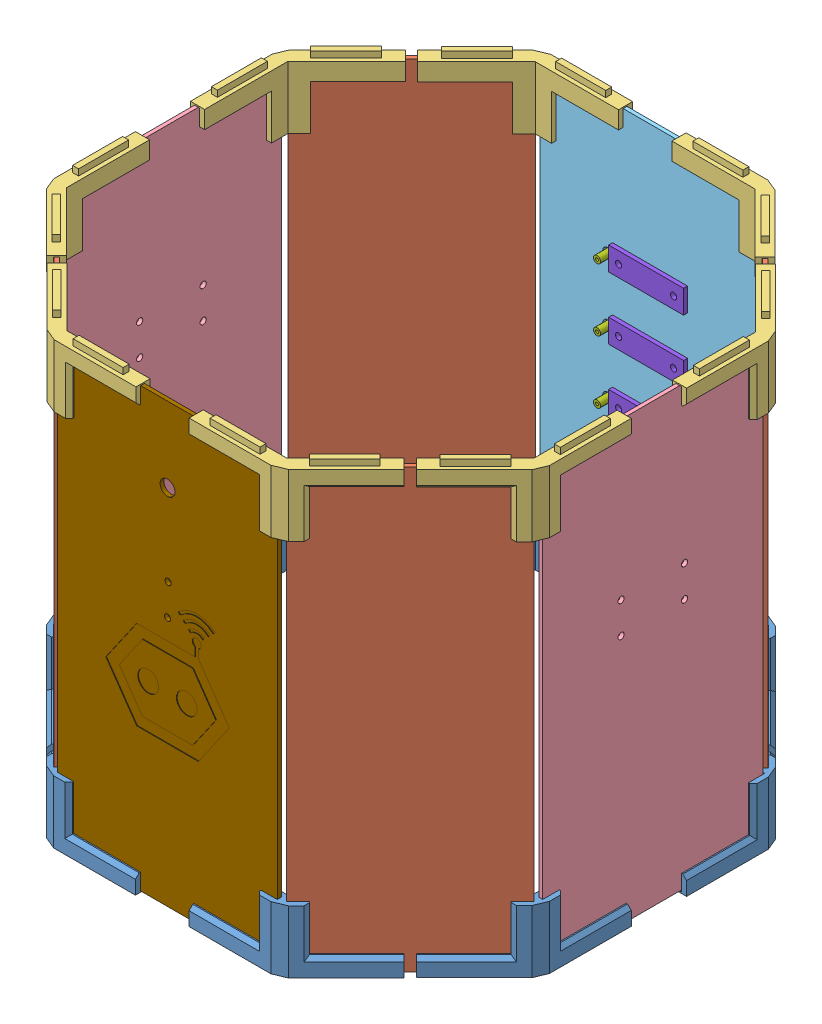
SolidWorks assembly Assem_Body_turtle, configuration Default. Lengths in mm.
Overall size (469.21 357 467.86).
41 component instances, 9 part files, 74 mates.
Components (placement in the parent):
- Links_ButtomOfBody-1: Links_ButtomOfBody [Default] at (-117.5632 60.4705 15.387) size (58.32 50 121.51)
- Body_Angled_Panel_Turtle-1: Body_Angled_Panel_Turtle [Default] at (-124.2129 61.4705 12.4372) x (0.707106 0 -0.707108) z (0 -1 0) size (140 3 350)
- Links_ButtomOfBody-2: Links_ButtomOfBody [Default] at (-17.44 60.4705 -81.6082) x (0.707108 0 0.707106) z (-0.707106 0 0.707108) size (58.32 50 121.51)
- Links_ButtomOfBody-3: Links_ButtomOfBody [Default] at (-120.488 60.4705 190.7707) x (0.707108 0 -0.707106) z (0.707106 0 0.707108) size (58.32 50 121.51)
- Links_ButtomOfBody-4: Links_ButtomOfBody [Default] at (158.1559 60.4705 -79.6088) x (0.000004 0 1) z (-1 0 0.000004) size (58.32 50 121.51)
- Body_Angled_Panel_Turtle-2: Body_Angled_Panel_Turtle [Default] at (161.1056 61.4705 -86.2586) x (0.707111 0 0.707103) z (0 -1 0) size (140 3 350)
- Body_Angled_Panel_Turtle-3: Body_Angled_Panel_Turtle [Default] at (-125.2256 411.4705 198.3367) x (0.707106 0 0.707108) z (0 1 0) size (140 3 350)
- Links_ButtomOfBody-5: Links_ButtomOfBody [Default] at (255.3635 60.4705 20.3019) x (-0.707103 0 0.707111) z (-0.707111 0 -0.707103) size (58.32 50 121.51)
- Links_ButtomOfBody-6: Links_ButtomOfBody [Default] at (-23.2811 60.4705 290.6821) x (0.000004 0 -1) z (1 0 0.000004) size (58.32 50 121.51)
- Links_ButtomOfBody-7: Links_ButtomOfBody [Default] at (152.3148 60.4705 292.8948) x (-0.707103 0 -0.707111) z (0.707111 0 -0.707103) size (58.32 50 121.51)
- Body_Angled_Panel_Turtle-4: Body_Angled_Panel_Turtle [Default] at (159.8808 411.4705 297.6325) x (0.707111 0 -0.707103) z (0 1 0) size (140 3 350)
- Links_ButtomOfBody-8: Links_ButtomOfBody [Default] at (252.0144 60.4705 195.4761) x (-1 0 -0.000007) z (0.000007 0 -1) size (58.32 50 121.51)
- Links_TopOfBody-1: Links_TopOfBody [Default] at (156.7189 412.4705 290.7706) x (0.000004 0 -1) z (-1 0 -0.000004) size (58.32 55 121.51)
- Links_TopOfBody-2: Links_TopOfBody [Default] at (254.1387 412.4705 191.072) x (-0.707103 0 -0.707111) z (-0.707111 0 0.707103) size (58.32 55 121.51)
- Links_TopOfBody-3: Links_TopOfBody [Default] at (-18.4526 412.4705 292.3821) x (0.707108 0 -0.707106) z (-0.707106 0 -0.707108) size (58.32 55 121.51)
- Links_TopOfBody-4: Links_TopOfBody [Default] at (-118.5758 412.4705 195.387) x (1 0 0) z (0 0 -1) size (58.32 55 121.51)
- Links_TopOfBody-5: Links_TopOfBody [Default] at (-22.0563 412.4705 -79.696) x (0.000004 0 1) z (1 0 -0.000004) size (58.32 55 121.51)
- Links_TopOfBody-6: Links_TopOfBody [Default] at (-119.4753 412.4705 20.0033) x (0.707108 0 0.707106) z (0.707106 0 -0.707108) size (58.32 55 121.51)
- Links_TopOfBody-7: Links_TopOfBody [Default] at (153.3274 412.4705 -81.3088) x (-0.707103 0 0.707111) z (0.707111 0 0.707103) size (58.32 55 121.51)
- Links_TopOfBody-8: Links_TopOfBody [Default] at (253.4513 412.4705 15.6857) x (-1 0 0.000007) z (0.000007 0 1) size (58.32 55 121.51)
- Body_Side_Panel_Turtle-3: Body_Side_Panel_Turtle [Default] at (-124.2758 61.4705 17.387) x (0 0 1) z (0 -1 0) size (176 3 350)
- Front_Panel_aluminiumContact_Turtle-1: Front_Panel_aluminiumContact_Turtle [Default] at (-275.2247 514.6339 -363.4416) x (1 0 -0.000004) z (0 -0.999584 -0.02885) size (176 20.62 349.94)
  - Body_Front_Panel_aluContact_Turtle-1: Body_Front_Panel_aluContact_Turtle [Default] at (255.1674 288.3056 445.031) x (1 0 0) z (0 0.02885 0.999584) size (176 3 350)
  - ContactAluFer-1: ContactAluFer [Default] at (317.0703 243.8583 286.4012) x (1 0 0) z (0 0.02885 0.999584) size (80 15.57 25.3)
    - Contact_barreAlu-1: Contact_barreAlu [Default] at (-13.9029 35.8024 53.6961) size (80 3.2 25.3)
    - ConnecteurAAnneau-1: ConnecteurAAnneau [Default] at (4.0971 39.0024 66.3461) x (0 0 1) z (-1 0 0) size (11.92 12.37 20.64)
    - Contact_barreFer-1: Contact_barreFer [Default] at (-3.9029 42.8524 75.6811) size (60 3.15 18.67)
  - ContactAluFer-2: ContactAluFer [Default] at (317.0703 240.9733 186.4428) x (1 0 0) z (0 0.02885 0.999584) size (80 15.57 25.3)
    - Contact_barreAlu-1: Contact_barreAlu [Default] at (-13.9029 35.8024 53.6961) size (80 3.2 25.3)
    - ConnecteurAAnneau-1: ConnecteurAAnneau [Default] at (4.0971 39.0024 66.3461) x (0 0 1) z (-1 0 0) size (11.92 12.37 20.64)
    - Contact_barreFer-1: Contact_barreFer [Default] at (-3.9029 42.8524 75.6811) size (60 3.15 18.67)
  - ContactAluFer-3: ContactAluFer [Default] at (317.0703 239.5308 136.4636) x (1 0 0) z (0 0.02885 0.999584) size (80 15.57 25.3)
    - Contact_barreAlu-1: Contact_barreAlu [Default] at (-13.9029 35.8024 53.6961) size (80 3.2 25.3)
    - ConnecteurAAnneau-1: ConnecteurAAnneau [Default] at (4.0971 39.0024 66.3461) x (0 0 1) z (-1 0 0) size (11.92 12.37 20.64)
    - Contact_barreFer-1: Contact_barreFer [Default] at (-3.9029 42.8524 75.6811) size (60 3.15 18.67)
  - ContactAluFer-4: ContactAluFer [Default] at (317.0703 242.4158 236.422) x (1 0 0) z (0 0.02885 0.999584) size (80 15.57 25.3)
    - Contact_barreAlu-1: Contact_barreAlu [Default] at (-13.9029 35.8024 53.6961) size (80 3.2 25.3)
    - ConnecteurAAnneau-1: ConnecteurAAnneau [Default] at (4.0971 39.0024 66.3461) x (0 0 1) z (-1 0 0) size (11.92 12.37 20.64)
    - Contact_barreFer-1: Contact_barreFer [Default] at (-3.9029 42.8524 75.6811) size (60 3.15 18.67)
- Body_Side_Panel_Turtle-4: Body_Side_Panel_Turtle [Default] at (257.9265 61.4705 193.6883) x (0.000007 0 -1) z (0 -1 0) size (176 3 350)
- Body_Back_Panel_Turtle-1: Body_Back_Panel_Turtle [Default] at (154.931 61.4705 299.6827) x (-1 0 -0.000004) z (0 -1 0) size (176 3 350)
Mates (geometry in assembly coordinates):
- Coincident59: coincident anti-aligned: plane of CoinButtom_Bas-1 through (-112.8992 110.4705 5.3661) normal (-0.707108 0 -0.707106); plane of Side_angle-1 through (-122.0916 61.4705 14.5585) normal (0.707108 0 0.707106)
- Coincident60: coincident anti-aligned: plane of CoinButtom_Bas-1 through (-112.8992 61.4705 5.3661) normal (0 1 0); plane of Side_angle-1 through (-122.0916 61.4705 14.5585) normal (0 -1 0)
- Coincident61: coincident anti-aligned: plane of CoinButtom_Bas-1 through (-122.0916 110.4705 14.5585) normal (0.707106 0 -0.707108); plane of Side_angle-1 through (-122.0916 61.4705 14.5585) normal (-0.707106 0 0.707108)
- Coincident62: coincident anti-aligned: plane of CoinButtom_Bas-2 through (-25.2181 110.4705 -86.5579) normal (0.707108 0 0.707106); plane of Side_angle-1 through (-124.2129 61.4705 12.4372) normal (-0.707108 0 -0.707106)
- Coincident63: coincident anti-aligned: plane of Side_angle-1 through (-23.0968 61.4705 -84.4366) normal (0.707106 0 -0.707108); plane of CoinButtom_Bas-2 through (-22.8847 110.4705 -84.2245) normal (-0.707106 0 0.707108)
- Coincident64: coincident anti-aligned: plane of Side_angle-1 through (-122.0916 61.4705 14.5585) normal (0 -1 0); plane of CoinButtom_Bas-2 through (-32.0771 61.4705 -75.032) normal (0 1 0)
- Coincident75: coincident anti-aligned: plane of CoinButtom_Bas-4 through (168.1767 110.4705 -74.9449) normal (0.707103 0 -0.707111); plane of Side_angle-2 through (158.9843 61.4705 -84.1372) normal (-0.707103 0 0.707111)
- Coincident76: coincident anti-aligned: plane of CoinButtom_Bas-4 through (168.1767 61.4705 -74.9449) normal (0 1 0); plane of Side_angle-2 through (158.9843 61.4705 -84.1372) normal (0 -1 0)
- Coincident77: coincident anti-aligned: plane of CoinButtom_Bas-4 through (158.9843 110.4705 -84.1372) normal (0.707111 0 0.707103); plane of Side_angle-2 through (158.9843 61.4705 -84.1372) normal (-0.707111 0 -0.707103)
- Coincident79: coincident anti-aligned: plane of Links_ButtomOfBody-3 through (-113.9119 110.4705 205.4078) normal (-0.707108 0 0.707106); plane of Side_angle-3 through (-123.1043 411.4705 196.2154) normal (0.707108 0 -0.707106)
- Coincident80: coincident anti-aligned: plane of Links_ButtomOfBody-3 through (-123.1043 110.4705 196.2154) normal (0.707106 0 0.707108); plane of Side_angle-3 through (-123.1043 411.4705 196.2154) normal (-0.707106 0 -0.707108)
- Coincident81: coincident anti-aligned: plane of Links_ButtomOfBody-3 through (-113.9119 61.4705 205.4078) normal (0 1 0); plane of Side_angle-3 through (-123.1043 61.4705 196.2154) normal (0 -1 0)
- Coincident85: coincident anti-aligned: plane of Side_angle-3 through (-123.1043 411.4705 196.2154) normal (0.707108 0 -0.707106); plane of Links_ButtomOfBody-6 through (-33.3019 110.4705 286.0181) normal (-0.707108 0 0.707106)
- Coincident86: coincident anti-aligned: plane of Side_angle-3 through (-123.1043 61.4705 196.2154) normal (0 -1 0); plane of Links_ButtomOfBody-6 through (-33.3019 61.4705 286.0181) normal (0 1 0)
- Coincident87: coincident anti-aligned: plane of Side_angle-3 through (-24.1095 411.4705 295.2105) normal (0.707106 0 0.707108); plane of Links_ButtomOfBody-6 through (-24.1095 110.4705 295.2105) normal (-0.707106 0 -0.707108)
- Coincident94: coincident anti-aligned: plane of Links_ButtomOfBody-7 through (166.9519 110.4705 286.3188) normal (0.707103 0 0.707111); plane of Side_angle-4 through (157.7595 411.4705 295.5111) normal (-0.707103 0 -0.707111)
- Coincident95: coincident anti-aligned: plane of Links_ButtomOfBody-7 through (157.7595 110.4705 295.5111) normal (0.707111 0 -0.707103); plane of Side_angle-4 through (157.7595 411.4705 295.5111) normal (-0.707111 0 0.707103)
- Coincident96: coincident anti-aligned: plane of Links_ButtomOfBody-7 through (166.9519 61.4705 286.3188) normal (0 1 0); plane of Side_angle-4 through (157.7595 61.4705 295.5111) normal (0 -1 0)
- Coincident97: coincident anti-aligned: plane of Side_angle-4 through (159.8808 411.4705 297.6325) normal (0.707103 0 0.707111); plane of Links_ButtomOfBody-8 through (258.8763 110.4705 198.6381) normal (-0.707103 0 -0.707111)
- Coincident99: coincident anti-aligned: plane of Side_angle-4 through (256.7549 411.4705 196.5167) normal (0.707111 0 -0.707103); plane of Links_ButtomOfBody-8 through (256.5428 110.4705 196.3046) normal (-0.707111 0 0.707103)
- Coincident109: coincident anti-aligned: plane of Side_angle-4 through (157.7595 411.4705 295.5111) normal (-0.707103 0 -0.707111); plane of Links_TopOfBody-2 through (247.5625 362.4705 205.7091) normal (0.707103 0 0.707111)
- Coincident110: coincident anti-aligned: plane of Side_angle-4 through (256.7549 411.4705 196.5167) normal (0.707111 0 -0.707103); plane of Links_TopOfBody-2 through (256.7549 362.4705 196.5167) normal (-0.707111 0 0.707103)
- Coincident111: coincident anti-aligned: plane of Side_angle-4 through (157.7595 411.4705 295.5111) normal (0 1 0); plane of Links_TopOfBody-2 through (247.5625 411.4705 205.7091) normal (0 -1 0)
- Coincident116: coincident anti-aligned: plane of Side_angle-3 through (-123.1043 411.4705 196.2154) normal (0.707108 0 -0.707106); plane of Links_TopOfBody-4 through (-113.9119 362.4705 205.4078) normal (-0.707108 0 0.707106)
- Coincident117: coincident anti-aligned: plane of Side_angle-3 through (-123.1043 411.4705 196.2154) normal (-0.707106 0 -0.707108); plane of Links_TopOfBody-4 through (-123.1043 362.4705 196.2154) normal (0.707106 0 0.707108)
- Coincident118: coincident anti-aligned: plane of Side_angle-3 through (-123.1043 411.4705 196.2154) normal (0 1 0); plane of Links_TopOfBody-4 through (-113.9119 411.4705 205.4078) normal (0 -1 0)
- Coincident128: coincident anti-aligned: plane of Side_angle-2 through (158.9843 61.4705 -84.1372) normal (-0.707103 0 0.707111); plane of Links_TopOfBody-8 through (248.7873 362.4705 5.6649) normal (0.707103 0 -0.707111)
- Coincident129: coincident anti-aligned: plane of Side_angle-2 through (257.9798 61.4705 14.8572) normal (0.707111 0 0.707103); plane of Links_TopOfBody-8 through (257.9798 362.4705 14.8572) normal (-0.707111 0 -0.707103)
- Coincident130: coincident anti-aligned: plane of Side_angle-2 through (158.9843 411.4705 -84.1372) normal (0 1 0); plane of Links_TopOfBody-8 through (248.7873 411.4705 5.6649) normal (0 -1 0)
- Coincident134: coincident anti-aligned: plane of Side_angle-3 through (-125.2256 411.4705 198.3367) normal (-0.707108 0 0.707106); plane of Links_TopOfBody-3 through (-26.2308 362.4705 297.3318) normal (0.707108 0 -0.707106)
- Coincident135: coincident anti-aligned: plane of Side_angle-3 through (-123.1043 411.4705 196.2154) normal (0 1 0); plane of Links_TopOfBody-3 through (-33.0897 411.4705 285.806) normal (0 -1 0)
- Coincident136: coincident aligned: line of Side_angle-3 through (-24.1095 411.4705 295.2105) axis (-0.707108 0 0.707106); line of Links_TopOfBody-3 through (-23.8974 411.4705 294.9984) axis (-0.707108 0 0.707106)
- Coincident140: coincident anti-aligned: plane of Side_angle-1 through (-122.0916 61.4705 14.5585) normal (-0.707106 0 0.707108); plane of Links_TopOfBody-6 through (-122.0916 362.4705 14.5585) normal (0.707106 0 -0.707108)
- Coincident141: coincident anti-aligned: plane of Side_angle-1 through (-122.0916 61.4705 14.5585) normal (0.707108 0 0.707106); plane of Links_TopOfBody-6 through (-112.8992 362.4705 5.3661) normal (-0.707108 0 -0.707106)
- Coincident142: coincident aligned: line of Side_angle-1 through (-122.0916 411.4705 14.5585) axis (-0.707108 0 -0.707106); line of Links_TopOfBody-6 through (-122.0916 411.4705 14.5585) axis (-0.707108 0 -0.707106)
- Coincident149: coincident anti-aligned: plane of Links_ButtomOfBody-5 through (259.1514 110.4705 30.6856) normal (1 0 -0.000007); plane of Side_court_avant_turtle-1 through (259.1513 61.4705 17.6856) normal (-1 0 0.000007)
- Coincident150: coincident anti-aligned: plane of Links_ButtomOfBody-5 through (259.1514 61.4705 30.6856) normal (0 1 0); plane of Side_court_avant_turtle-1 through (259.1513 61.4705 17.6856) normal (0 -1 0)
- Coincident151: coincident aligned: line of Links_TopOfBody-8 through (259.1513 411.4705 17.6856) axis (1 0 -0.000007); line of Side_court_avant_turtle-1 through (259.1513 411.4705 17.6856) axis (1 0 -0.000007)
- Coincident152: coincident anti-aligned: plane of Side_angle-2 through (158.9843 411.4705 -84.1372) normal (0 1 0); plane of Links_TopOfBody-7 through (167.9646 411.4705 -74.7328) normal (0 -1 0)
- Coincident153: coincident anti-aligned: plane of Links_ButtomOfBody-8 through (257.7145 61.4705 180.4762) normal (0 1 0); plane of Side_court_avant_turtle-1 through (259.1513 61.4705 17.6856) normal (0 -1 0)
- Coincident154: coincident anti-aligned: plane of Side_angle-4 through (157.7595 411.4705 295.5111) normal (0 1 0); plane of Links_TopOfBody-1 through (166.7398 411.4705 286.1067) normal (0 -1 0)
- Coincident155: coincident anti-aligned: plane of Side_angle-4 through (157.7595 411.4705 295.5111) normal (-0.707111 0 0.707103); plane of Links_TopOfBody-1 through (157.5473 362.4705 295.299) normal (0.707111 0 -0.707103)
- Coincident156: coincident anti-aligned: plane of Side_angle-4 through (159.8808 411.4705 297.6325) normal (0.707103 0 0.707111); plane of Links_TopOfBody-1 through (159.8808 362.4705 297.6325) normal (-0.707103 0 -0.707111)
- Coincident157: coincident anti-aligned: plane of Links_ButtomOfBody-3 through (-124.2758 110.4705 180.387) normal (-1 0 0); plane of Side_court_turtle-3 through (-124.2758 61.4705 17.387) normal (1 0 0)
- Coincident161: coincident anti-aligned: plane of Links_ButtomOfBody-3 through (-124.2758 61.4705 180.387) normal (0 1 0); plane of Side_court_turtle-3 through (-127.2758 61.4705 17.387) normal (0 -1 0)
- Coincident162: coincident anti-aligned: line of Links_ButtomOfBody-3 through (-124.2758 61.4705 193.387) axis (-1 0 0); line of Side_court_turtle-3 through (-127.2758 61.4705 193.387) axis (1 0 0)
- Coincident163: coincident anti-aligned: plane of Links_TopOfBody-7 through (155.9437 362.4705 -88.3966) normal (0.000004 0 1); plane of Side_court_turtle-1 through (-20.0563 61.4705 -88.396) normal (-0.000004 0 -1)
- Coincident164: coincident anti-aligned: plane of Links_TopOfBody-7 through (142.9437 411.4705 -85.0966) normal (0 -1 0); plane of Side_court_turtle-1 through (-20.0563 411.4705 -85.396) normal (0 1 0)
- Coincident165: coincident aligned: line of Links_TopOfBody-7 through (155.9437 411.4705 -85.0966) axis (-0.000004 0 -1); line of Side_court_turtle-1 through (155.9437 411.4705 -85.3966) axis (-0.000004 0 -1)
- Coincident166: coincident anti-aligned: plane of Links_TopOfBody-1 through (141.7189 362.4705 296.4705) normal (-0.000004 0 1); plane of Side_court_turtle-2 through (-21.2811 61.4705 296.47) normal (0.000004 0 -1)
- Coincident167: coincident anti-aligned: plane of Links_TopOfBody-1 through (141.7189 411.4705 296.4705) normal (0 -1 0); plane of Side_court_turtle-2 through (-21.2811 411.4705 299.47) normal (0 1 0)
- Coincident168: coincident anti-aligned: line of Links_TopOfBody-1 through (154.7189 411.4705 296.4706) axis (-0.000004 0 1); line of Side_court_turtle-2 through (154.7189 411.4705 299.4706) axis (0.000004 0 -1)
- Coincident169: coincident anti-aligned: plane of Links_TopOfBody-3 through (-8.069 411.4705 296.17) normal (0 -1 0); plane of Side_court_turtle-2 through (-21.2811 411.4705 299.47) normal (0 1 0)
- Coincident170: coincident anti-aligned: plane of Links_TopOfBody-3 through (-21.069 362.4705 299.47) normal (0.000004 0 -1); plane of Side_court_turtle-2 through (-21.2811 61.4705 299.47) normal (-0.000004 0 1)
- Coincident171: coincident: line of Links_ButtomOfBody-6 through (-21.2811 61.4705 296.3821) axis (-0.000004 0 1); plane of Side_court_turtle-2 through (-21.2811 61.4705 299.47) normal (-1 0 -0.000004)
- Coincident172: coincident anti-aligned: plane of Links_ButtomOfBody-1 through (-123.2632 61.4705 30.387) normal (0 1 0); plane of Side_court_turtle-3 through (-127.2758 61.4705 17.387) normal (0 -1 0)
- Coincident173: coincident: line of Links_TopOfBody-6 through (-126.5632 362.4705 17.387) axis (1 0 0); plane of Side_court_turtle-3 through (-127.2758 61.4705 17.387) normal (0 0 -1)
- Coincident174: coincident anti-aligned: plane of Side_angle-2 through (161.1056 61.4705 -86.2586) normal (0.707103 0 -0.707111); plane of Links_TopOfBody-7 through (161.1056 362.4705 -86.2586) normal (-0.707103 0 0.707111)
- Coincident175: coincident: plane of Side_angle-2 through (158.9843 61.4705 -84.1372) normal (-0.707111 0 -0.707103); line of Links_TopOfBody-7 through (161.1056 362.4705 -86.2586) axis (-0.707103 0 0.707111)
- Coincident178: coincident anti-aligned: plane of Links_ButtomOfBody-2 through (-20.0563 110.4705 -85.396) normal (1 0 -0.000004); plane of Side_court_turtle-1 through (-20.0563 61.4705 -85.396) normal (-1 0 0.000004)
- Coincident179: coincident anti-aligned: plane of Links_TopOfBody-5 through (-7.0563 362.4705 -85.3961) normal (-0.000004 0 -1); plane of Side_court_turtle-1 through (-20.0563 61.4705 -85.396) normal (0.000004 0 1)
- Coincident180: coincident anti-aligned: plane of Links_TopOfBody-5 through (-7.0563 411.4705 -85.3961) normal (0 -1 0); plane of Side_court_turtle-1 through (-20.0563 411.4705 -85.396) normal (0 1 0)
- Coincident181: coincident: line of Links_TopOfBody-5 through (-20.0563 362.4705 -88.696) axis (0.000004 0 1); plane of Side_court_turtle-1 through (-20.0563 61.4705 -85.396) normal (-1 0 0.000004)
- Coincident182: coincident anti-aligned: plane of Side_angle-1 through (-124.2129 61.4705 12.4372) normal (-0.707108 0 -0.707106); plane of Links_TopOfBody-5 through (-25.2181 362.4705 -86.5579) normal (0.707108 0 0.707106)
- Coincident183: coincident anti-aligned: plane of Side_angle-1 through (-122.0916 411.4705 14.5585) normal (0 1 0); plane of Links_TopOfBody-5 through (-32.0771 411.4705 -75.032) normal (0 -1 0)
- Coincident184: coincident anti-aligned: plane of Links_TopOfBody-2 through (257.9266 362.4705 180.6883) normal (1 0 0.000007); plane of Side_court_turtle-4 through (257.9265 61.4705 193.6883) normal (-1 0 -0.000007)
- Coincident185: coincident anti-aligned: plane of Links_TopOfBody-2 through (257.9266 411.4705 180.6883) normal (0 -1 0); plane of Side_court_turtle-4 through (260.9265 411.4705 193.6883) normal (0 1 0)
- Coincident186: coincident anti-aligned: line of Links_TopOfBody-2 through (257.9265 411.4705 193.6883) axis (1 0 0.000007); line of Side_court_turtle-4 through (260.9265 411.4705 193.6883) axis (-1 0 -0.000007)
- Coincident190: coincident anti-aligned: plane of Links_ButtomOfBody-7 through (141.931 110.4705 296.6827) normal (-0.000004 0 1); plane of Side_court_arriere_turtle-1 through (154.931 61.4705 296.6827) normal (0.000004 0 -1)
- Coincident191: coincident anti-aligned: plane of Links_ButtomOfBody-7 through (141.931 61.4705 296.6827) normal (0 1 0); plane of Side_court_arriere_turtle-1 through (154.931 61.4705 296.6827) normal (0 -1 0)
- Coincident192: coincident anti-aligned: plane of Links_ButtomOfBody-7 through (154.931 110.4705 296.6827) normal (-1 0 -0.000004); plane of Side_court_arriere_turtle-1 through (154.931 61.4705 296.6827) normal (1 0 0.000004)
- Coincident193: coincident anti-aligned: plane of Links_TopOfBody-7 through (142.9437 362.4705 -85.0966) normal (-0.000004 0 -1); plane of charge_turtle-1/Side_court_avant_turtle-1 through (-20.0563 61.4705 -85.096) normal (0.000004 0 1)
- Coincident194: coincident anti-aligned: plane of Links_TopOfBody-7 through (142.9437 411.4705 -85.0966) normal (0 -1 0); plane of charge_turtle-1/Side_court_avant_turtle-1 through (-20.0563 411.4705 -85.096) normal (0 1 0)
- Coincident195: coincident anti-aligned: plane of Links_TopOfBody-7 through (155.9437 362.4705 -85.0966) normal (-1 0 0.000004); plane of charge_turtle-1/Side_court_avant_turtle-1 through (155.9437 61.4705 -85.0966) normal (1 0 -0.000004)
